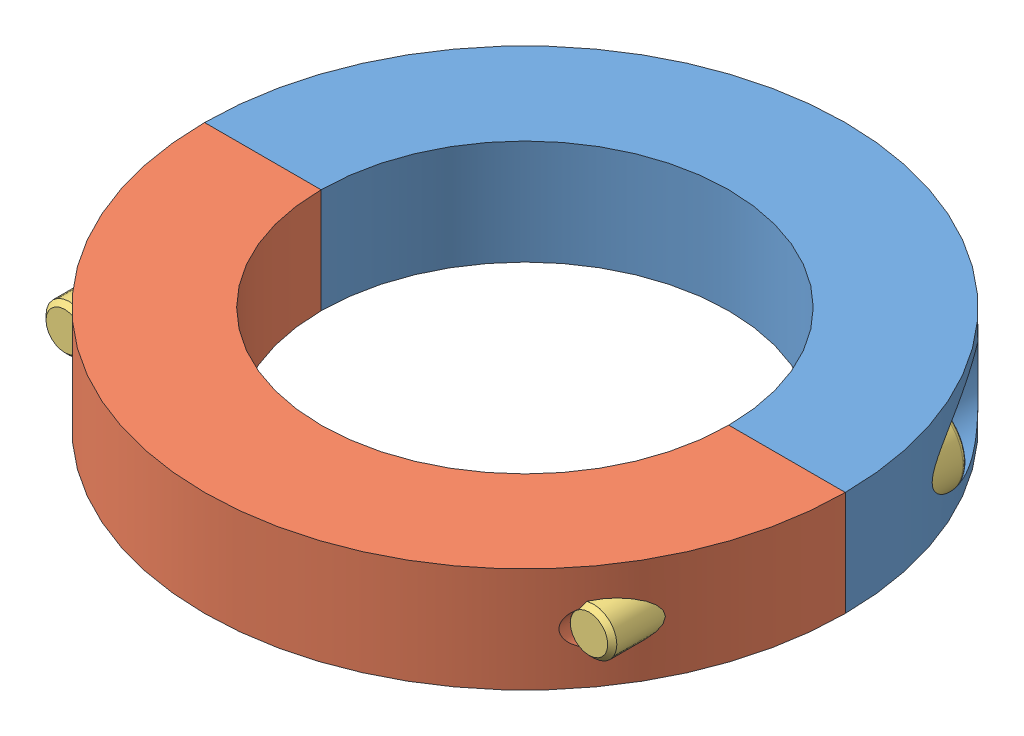
SolidWorks assembly Collar_Big_ass, configuration Default. Lengths in mm.
Overall size (55 24.37 55).
4 component instances, 3 part files, 7 mates.
Components (placement in the parent):
- Collar_second_half_big-1: Collar_second_half_big [Default] at (17.0586 22.4239 39.0806) size (55 24.37 27.5)
- Collar_one_half_big-2: Collar_one_half_big [Default] at (17.0586 22.4239 39.0806) x (-1 0 0) z (0 0 -1) size (55 24.37 27.5)
- socket head cap screw_din-3: socket head cap screw_din [DIN 912 M4 x 25 --- 25N] at (39.5586 22.4239 27.0806) x (0 0 1) z (-1 0 0) size (29 7 7)
- socket head cap screw_din-4: socket head cap screw_din [DIN 912 M4 x 25 --- 25N] at (-5.4414 22.4239 27.0806) x (0 0 1) z (-1 0 0) size (29 7 7)
Mates (geometry in assembly coordinates):
- Concentric2: concentric anti-aligned: circle of Collar_second_half_big-1; cylinder of Collar_one_half_big-2 through (39.5586 22.4239 39.0806) axis (0 0 -1) radius 1.65
- Concentric3: concentric anti-aligned: circle of Collar_second_half_big-1; cylinder of Collar_one_half_big-2 through (-5.4414 22.4239 39.0806) axis (0 0 -1) radius 1.65
- Coincident1: coincident anti-aligned: plane of Collar_second_half_big-1 through (34.5586 17.9239 39.0806) normal (0 0 1); plane of Collar_one_half_big-2 through (44.5586 26.9239 39.0806) normal (0 0 -1)
- Concentric4: concentric anti-aligned: cylinder of Collar_second_half_big-1 through (39.5586 22.4239 13.0806) axis (0 0 1) radius 3.5; cylinder of socket head cap screw_din-3 through (39.5586 22.4239 -4.6694) axis (0 0 -1) radius 3.5
- Coincident2: coincident anti-aligned: plane of Collar_second_half_big-1 through (39.5586 22.4239 31.0806) normal (0 0 -1); plane of socket head cap screw_din-3 through (39.5586 25.9239 31.0806) normal (0 0 1)
- Concentric5: concentric anti-aligned: cylinder of Collar_second_half_big-1 through (-5.4414 22.4239 13.0806) axis (0 0 1) radius 3.5; cylinder of socket head cap screw_din-4 through (-5.4414 22.4239 -4.6694) axis (0 0 -1) radius 3.5
- Coincident3: coincident anti-aligned: plane of Collar_second_half_big-1 through (-5.4414 22.4239 31.0806) normal (0 0 -1); plane of socket head cap screw_din-4 through (-5.4414 25.9239 31.0806) normal (0 0 1)
